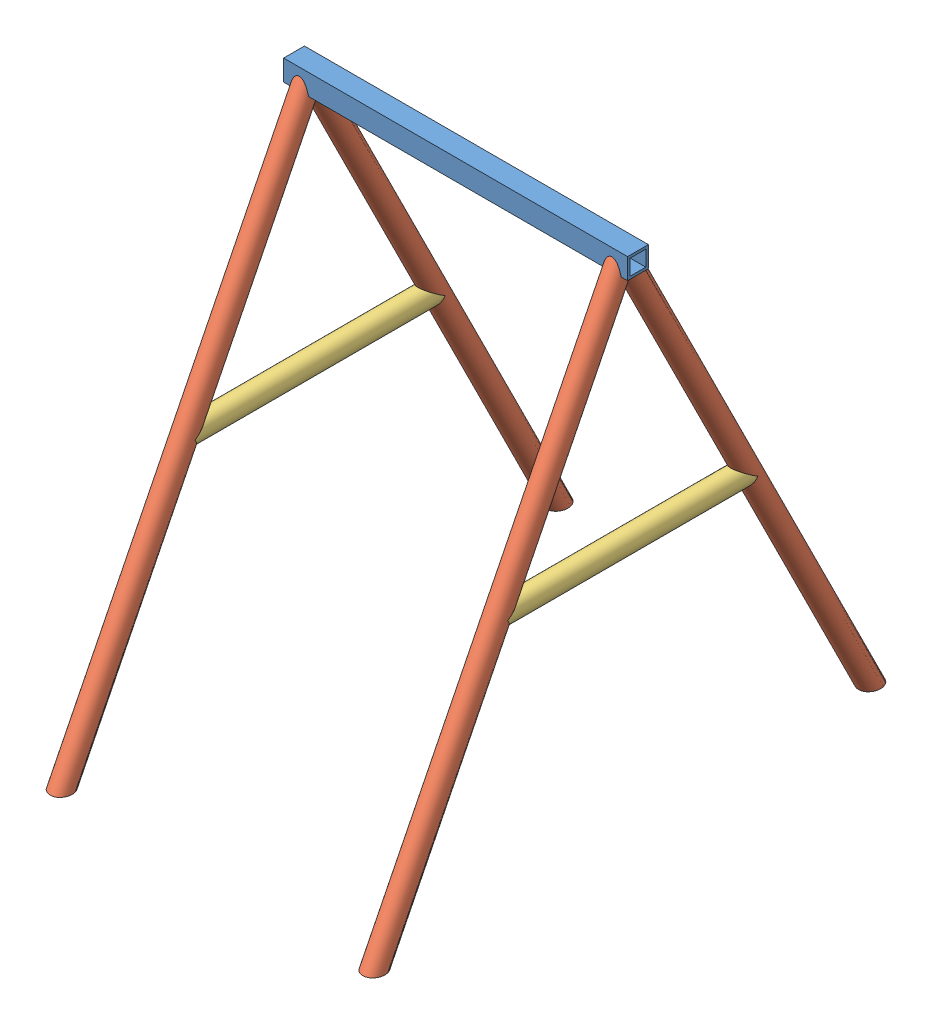
SolidWorks assembly fs2jackstand, configuration Default. Lengths in mm.
Overall size (419.1 616.62 632.32).
7 component instances, 3 part files, 12 mates.
Components (placement in the parent):
- Top Bar^fs2jackstand-1: Top Bar^fs2jackstand [Default] x (0 0 -1) z (1 0 0) size (25.4 25.4 419.1) (virtual)
- Leg^fs2jackstand-1: Leg^fs2jackstand [Default] at (0 -609.6 0) x (1 0 0) z (0 1 0) size (25.4 316.16 606.92) (virtual)
- Leg^fs2jackstand-2: Leg^fs2jackstand [Default] at (381 -609.6 0) x (-1 0 0) z (0 1 0) size (25.4 316.16 606.92) (virtual)
- Leg^fs2jackstand-3: Leg^fs2jackstand [Default] at (-381 -609.6 0) x (1 0 0) z (0 1 0) size (25.4 316.16 606.92) (virtual)
- Leg^fs2jackstand-4: Leg^fs2jackstand [Default] at (0 -609.6 0) x (-1 0 0) z (0 1 0) size (25.4 316.16 606.92) (virtual)
- Brace Bar^fs2jackstand-1: Brace Bar^fs2jackstand [Default] at (190.5 -304.8 152.4) size (25.4 25.4 304.8) (virtual)
- Brace Bar^fs2jackstand-3: Brace Bar^fs2jackstand [Default] at (-190.5 -304.8 -152.4) x (-1 0 0) z (0 0 -1) size (25.4 25.4 304.8) (virtual)
Mates (geometry in assembly coordinates):
- InPlace1: in place: plane of Top Bar^fs2jackstand-1 through (0 0 0) normal (1 0 0); moOrthogonalPlaneRef_w of Top Bar^fs2jackstand-1 through (0 0 0) normal (0 1 0); plane of Top Bar^fs2jackstand-1 through (0 0 0) normal (0 0 -1); unknown of Top Bar^fs2jackstand-1
- Coincident1: coincident aligned: 
- Coincident2: coincident aligned: plane of Part1^fs2jackstand-1 through (0 0 0) normal (0 1 0)
- Coincident3: coincident anti-aligned: plane of Part1^fs2jackstand-1 through (0 0 0) normal (0 0 -1)
- InPlace2: in place: plane of Leg^fs2jackstand-1 through (0 -609.6 0) normal (0 1 0); plane of Leg^fs2jackstand-1 through (0 -609.6 0) normal (0 0 -1); plane of Leg^fs2jackstand-1 through (0 -609.6 0) normal (1 0 0); unknown of Leg^fs2jackstand-1
- Coincident4: coincident aligned: 
- Coincident5: coincident aligned: plane of Part3^fs2jackstand-1 through (0 -609.6 0) normal (0 0 -1)
- Coincident6: coincident anti-aligned: plane of Part3^fs2jackstand-1 through (0 -609.6 0) normal (1 0 0)
- InPlace3: in place: plane of ? through (165.1 -304.8 152.4) normal (0 0 1); plane of ? through (165.1 -304.8 152.4) normal (0 1 0); plane of ? through (165.1 -304.8 152.4) normal (1 0 0); unknown of Brace Bar^fs2jackstand-1
- Coincident7: coincident aligned: 
- Coincident8: coincident aligned: plane of Part5^fs2jackstand-1 through (190.5 -304.8 152.4) normal (0 1 0)
- Coincident9: coincident anti-aligned: plane of Part5^fs2jackstand-1 through (190.5 -304.8 152.4) normal (1 0 0)
